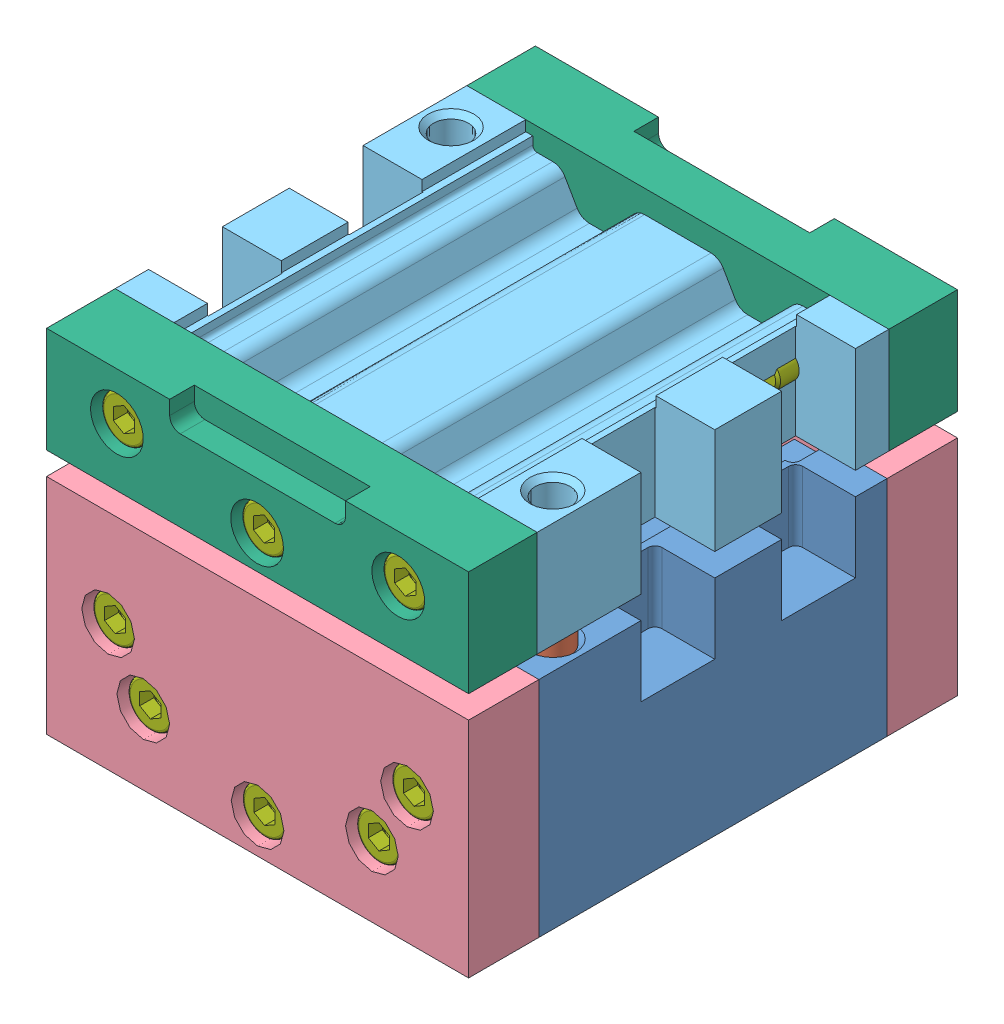
SolidWorks assembly Сборка, configuration По умолчанию. Lengths in mm.
Overall size (120 100 139).
26 component instances, 7 part files, 58 mates.
Components (placement in the parent):
- Матрица пресс-формы трак-1: Матрица пресс-формы трак [По умолчанию] at (94.4955 113.7729 76.599) x (-1 0 0) z (0 -1 0) size (120 99 63.5)
- Направляющая-1: Направляющая [По умолчанию] at (134.3195 83.7729 119.5159) x (0 1 0) z (-0.942376 0 0.334555) size (55 10 10)
- Направляющая-2: Направляющая [По умолчанию] at (30.3195 83.7729 44.5159) x (0 1 0) z (-0.954844 0 0.297108) size (55 10 10)
- Подстановка-1: Подстановка [По умолчанию] at (85.2823 100.5229 55.4864) x (0 1 0) z (-0.987622 0 -0.156852) size (36.5 12 12)
- Подстановка-2: Подстановка [По умолчанию] at (83.6486 100.5229 111.7054) x (0 1 0) z (-0.443057 0 -0.896493) size (36.5 12 12)
- Боковина пресс-формы-1: Боковина пресс-формы [По умолчанию] at (82.3195 82.0229 131.5159) x (1 0 0) z (0 -1 0) size (120 20 63.5)
- Боковина пресс-формы-2: Боковина пресс-формы [По умолчанию] at (82.3195 82.0229 32.5159) x (-1 0 0) z (0 -1 0) size (120 20 63.5)
- Пуансон (на бис, дымись канабис)-2: Пуансон (на бис, дымись канабис) [По умолчанию] at (69.8379 150.2729 72.2482) x (-1 0 0) z (0 0 1) size (120 30 100)
- Боковина пуансона-5: Боковина пуансона [По умолчанию] at (82.3195 135.2729 132.0159) x (1 0 0) z (0 -1 0) size (120 19.5 30)
- Боковина пуансона-6: Боковина пуансона [По умолчанию] at (82.3195 135.2729 32.0159) x (-1 0 0) z (0 -1 0) size (120 19.5 30)
- socket head cap screw 4762_din-2: socket head cap screw 4762_din [EN ISO 4762 M8 x 25 - 25S] at (114.8195 70.2729 149.5159) x (0 0 -1) z (1 0 0) size (33 13 13)
- socket head cap screw 4762_din-3: socket head cap screw 4762_din [EN ISO 4762 M8 x 25 - 25S] at (82.3195 60.2729 149.5159) x (0 0 -1) z (1 0 0) size (33 13 13)
- socket head cap screw 4762_din-4: socket head cap screw 4762_din [EN ISO 4762 M8 x 25 - 25S] at (49.8195 70.2729 149.5159) x (0 0 -1) z (1 0 0) size (33 13 13)
- socket head cap screw 4762_din-6: socket head cap screw 4762_din [EN ISO 4762 M8 x 25 - 25N] at (124.8195 86.2729 149.5159) x (0 0 -1) z (1 0 0) size (33 13 13)
- socket head cap screw 4762_din-7: socket head cap screw 4762_din [EN ISO 4762 M8 x 25 - 25N] at (39.8195 86.2729 149.5159) x (0 0 -1) z (1 0 0) size (33 13 13)
- socket head cap screw 4762_din-8: socket head cap screw 4762_din [EN ISO 4762 M8 x 25 - 25N] at (39.8195 86.2729 14.5159) x (0 0 1) z (-1 0 0) size (33 13 13)
- socket head cap screw 4762_din-9: socket head cap screw 4762_din [EN ISO 4762 M8 x 25 - 25N] at (49.8195 70.2729 14.5159) x (0 0 1) z (-1 0 0) size (33 13 13)
- socket head cap screw 4762_din-10: socket head cap screw 4762_din [EN ISO 4762 M8 x 25 - 25N] at (82.3195 60.2729 14.5159) x (0 0 1) z (-1 0 0) size (33 13 13)
- socket head cap screw 4762_din-11: socket head cap screw 4762_din [EN ISO 4762 M8 x 25 - 25N] at (114.8195 70.2729 14.5159) x (0 0 1) z (-1 0 0) size (33 13 13)
- socket head cap screw 4762_din-12: socket head cap screw 4762_din [EN ISO 4762 M8 x 25 - 25N] at (124.8195 86.2729 14.5159) x (0 0 1) z (-1 0 0) size (33 13 13)
- socket head cap screw 4762_din-13: socket head cap screw 4762_din [EN ISO 4762 M8 x 25 - 25N] at (122.3195 136.7729 149.5159) x (0 0 -1) z (1 0 0) size (33 13 13)
- socket head cap screw 4762_din-14: socket head cap screw 4762_din [EN ISO 4762 M8 x 25 - 25N] at (82.18 129.7729 149.5159) x (0 0 -1) z (1 0 0) size (33 13 13)
- socket head cap screw 4762_din-15: socket head cap screw 4762_din [EN ISO 4762 M8 x 25 - 25N] at (42.3195 136.7729 149.5159) x (0 0 -1) z (1 0 0) size (33 13 13)
- socket head cap screw 4762_din-16: socket head cap screw 4762_din [EN ISO 4762 M8 x 25 - 25N] at (42.3195 136.7729 14.5159) x (0 0 1) z (-1 0 0) size (33 13 13)
- socket head cap screw 4762_din-17: socket head cap screw 4762_din [EN ISO 4762 M8 x 25 - 25N] at (82.4589 129.7729 14.5159) x (0 0 1) z (-1 0 0) size (33 13 13)
- socket head cap screw 4762_din-18: socket head cap screw 4762_din [EN ISO 4762 M8 x 25 - 25N] at (122.3195 136.7729 14.5159) x (0 0 1) z (-1 0 0) size (33 13 13)
Mates (geometry in assembly coordinates):
- Совпадение1: coincident anti-aligned: plane of Матрица пресс-формы трак-1 through (134.3195 83.7729 119.5159) normal (0 1 0); plane of Направляющая-1 through (134.3195 83.7729 119.5159) normal (0 -1 0)
- Концентричный2: concentric anti-aligned: cylinder of Матрица пресс-формы трак-1 through (134.3195 83.7729 119.5159) axis (0 1 0) radius 5; cylinder of Направляющая-1 through (134.3195 83.7729 119.5159) axis (0 -1 0) radius 5
- Совпадение2: coincident anti-aligned: plane of Матрица пресс-формы трак-1 through (30.3195 83.7729 44.5159) normal (0 1 0); plane of Направляющая-2 through (30.3195 83.7729 44.5159) normal (0 -1 0)
- Концентричный3: concentric anti-aligned: cylinder of Матрица пресс-формы трак-1 through (30.3195 83.7729 44.5159) axis (0 1 0) radius 5; cylinder of Направляющая-2 through (30.3195 83.7729 44.5159) axis (0 -1 0) radius 5
- Совпадение3: coincident anti-aligned: plane of Матрица пресс-формы трак-1 through (82.3195 83.7729 55.0159) normal (0 1 0); plane of Подстановка-1 through (82.3195 83.7729 55.0159) normal (0 -1 0)
- Концентричный4: concentric anti-aligned: cylinder of Матрица пресс-формы трак-1 through (82.3195 83.7729 55.0159) axis (0 1 0) radius 6; cylinder of Подстановка-1 through (82.3195 83.7729 55.0159) axis (0 -1 0) radius 6
- Совпадение4: coincident anti-aligned: plane of Матрица пресс-формы трак-1 through (82.3195 83.7729 109.0159) normal (0 1 0); plane of Подстановка-2 through (82.3195 83.7729 109.0159) normal (0 -1 0)
- Концентричный5: concentric anti-aligned: cylinder of Матрица пресс-формы трак-1 through (82.3195 83.7729 109.0159) axis (0 1 0) radius 6; cylinder of Подстановка-2 through (82.3195 83.7729 109.0159) axis (0 -1 0) radius 6
- Совпадение7: coincident anti-aligned: plane of Матрица пресс-формы трак-1 through (142.3195 50.2729 131.5159) normal (0 0 1); plane of Боковина пресс-формы-1 through (82.3195 82.0229 131.5159) normal (0 0 -1)
- Концентричный8: concentric aligned: cylinder of Матрица пресс-формы трак-1 through (82.3195 60.2729 101.5159) axis (0 0 1) radius 3.4; cylinder of Боковина пресс-формы-1 through (82.3195 60.2729 151.5159) axis (0 0 1) radius 4.25
- Концентричный9: concentric aligned: cylinder of Матрица пресс-формы трак-1 through (82.3195 60.2729 62.5159) axis (0 0 -1) radius 3.4; cylinder of Боковина пресс-формы-2 through (82.3195 60.2729 12.5159) axis (0 0 -1) radius 4.25
- Совпадение8: coincident anti-aligned: plane of Матрица пресс-формы трак-1 through (142.3195 50.2729 32.5159) normal (0 0 -1); plane of Боковина пресс-формы-2 through (82.3195 82.0229 32.5159) normal (0 0 1)
- Концентричный11: concentric aligned: cylinder of Направляющая-2 through (30.3195 83.7729 44.5159) axis (0 -1 0) radius 5; cylinder of Пуансон (на бис, дымись канабис)-2 through (30.3195 220.2729 44.5159) axis (0 -1 0) radius 5
- Совпадение9: coincident anti-aligned: circle of Подстановка-1; plane of Пуансон (на бис, дымись канабис)-2 through (69.8379 120.2729 72.2482) normal (0 -1 0)
- Концентричный14: concentric aligned: cylinder of Пуансон (на бис, дымись канабис)-2 through (122.3195 136.7729 105.2659) axis (0 0 1) radius 3.4; cylinder of Боковина пуансона-5 through (122.3195 136.7729 151.5159) axis (0 0 1) radius 4.5
- Совпадение11: coincident anti-aligned: plane of Пуансон (на бис, дымись канабис)-2 through (142.3195 120.2729 132.0159) normal (0 0 1); plane of Боковина пуансона-5 through (82.3195 135.2729 132.0159) normal (0 0 -1)
- Концентричный15: concentric aligned: cylinder of Пуансон (на бис, дымись канабис)-2 through (122.3195 136.7729 58.7659) axis (0 0 -1) radius 3.4; cylinder of Боковина пуансона-6 through (122.3195 136.7729 12.5159) axis (0 0 -1) radius 4.5
- Совпадение12: coincident anti-aligned: plane of Пуансон (на бис, дымись канабис)-2 through (142.3195 120.2729 32.0159) normal (0 0 -1); plane of Боковина пуансона-6 through (82.3195 135.2729 32.0159) normal (0 0 1)
- Параллельность1: parallel aligned: cylinder of Направляющая-1 through (134.3195 83.7729 119.5159) axis (0 -1 0) radius 5; cylinder of Пуансон (на бис, дымись канабис)-2 through (134.2575 220.2729 119.5159) axis (0 -1 0) radius 5
- Концентричный17: concentric aligned: cylinder of Направляющая-2 through (30.3195 83.7729 44.5159) axis (0 -1 0) radius 5; cylinder of Пуансон (на бис, дымись канабис)-2 through (30.3195 220.2729 44.5159) axis (0 -1 0) radius 5
- Совпадение13: coincident aligned: plane of Пуансон (на бис, дымись канабис)-2 through (22.3195 120.2729 32.0159) normal (-1 0 0); plane of Боковина пуансона-5 through (22.3195 120.2729 151.5159) normal (-1 0 0)
- Совпадение14: coincident aligned: plane of Пуансон (на бис, дымись канабис)-2 through (22.3195 120.2729 32.0159) normal (-1 0 0); plane of Боковина пуансона-6 through (22.3195 120.2729 12.5159) normal (-1 0 0)
- Параллельность2: parallel aligned: cylinder of Боковина пресс-формы-1 through (124.8195 86.2729 151.5159) axis (0 0 1) radius 4.25; cylinder of Матрица пресс-формы трак-1 through (124.8195 86.2729 101.5159) axis (0 0 1) radius 3.4
- Совпадение16: coincident aligned: plane of Матрица пресс-формы трак-1 through (142.3195 50.2729 32.5159) normal (1 0 0); plane of Боковина пресс-формы-1 through (142.3195 50.2729 151.5159) normal (1 0 0)
- Совпадение17: coincident aligned: plane of Матрица пресс-формы трак-1 through (142.3195 50.2729 32.5159) normal (1 0 0); plane of Боковина пресс-формы-2 through (142.3195 50.2729 12.5159) normal (1 0 0)
- Совпадение18: coincident aligned: plane of Матрица пресс-формы трак-1 through (142.3195 50.2729 32.5159) normal (1 0 0); plane of Пуансон (на бис, дымись канабис)-2 through (142.3195 120.2729 32.0159) normal (1 0 0)
- Концентричный19: concentric aligned: cylinder of Боковина пресс-формы-1 through (114.8195 70.2729 151.5159) axis (0 0 1) radius 4.25; cylinder of socket head cap screw 4762_din-2 through (114.8195 70.2729 181.2659) axis (0 0 1) radius 6.5
- Совпадение20: coincident anti-aligned: plane of Боковина пресс-формы-1 through (119.0695 70.2729 141.5159) normal (0 0 1); plane of socket head cap screw 4762_din-2 through (114.8195 76.7729 141.5159) normal (0 0 -1)
- Концентричный20: concentric aligned: cylinder of Боковина пресс-формы-1 through (82.3195 60.2729 151.5159) axis (0 0 1) radius 7.5; cylinder of socket head cap screw 4762_din-3 through (82.3195 60.2729 181.2659) axis (0 0 1) radius 6.5
- Совпадение21: coincident anti-aligned: plane of Боковина пресс-формы-1 through (86.5695 60.2729 141.5159) normal (0 0 1); plane of socket head cap screw 4762_din-3 through (82.3195 66.7729 141.5159) normal (0 0 -1)
- Концентричный21: concentric aligned: cylinder of Боковина пресс-формы-1 through (49.8195 70.2729 151.5159) axis (0 0 1) radius 7.5; cylinder of socket head cap screw 4762_din-4 through (49.8195 70.2729 181.2659) axis (0 0 1) radius 6.5
- Совпадение22: coincident anti-aligned: plane of Боковина пресс-формы-1 through (54.0695 70.2729 141.5159) normal (0 0 1); plane of socket head cap screw 4762_din-4 through (49.8195 76.7729 141.5159) normal (0 0 -1)
- Концентричный23: concentric aligned: cylinder of Боковина пресс-формы-1 through (124.8195 86.2729 151.5159) axis (0 0 1) radius 4.25; cylinder of socket head cap screw 4762_din-6 through (124.8195 86.2729 181.2659) axis (0 0 1) radius 6.5
- Совпадение23: coincident anti-aligned: plane of Боковина пресс-формы-1 through (129.0695 86.2729 141.5159) normal (0 0 1); plane of socket head cap screw 4762_din-6 through (124.8195 92.7729 141.5159) normal (0 0 -1)
- Концентричный24: concentric aligned: cylinder of Боковина пресс-формы-1 through (39.8195 86.2729 151.5159) axis (0 0 1) radius 4.25; cylinder of socket head cap screw 4762_din-7 through (39.8195 86.2729 181.2659) axis (0 0 1) radius 6.5
- Совпадение24: coincident anti-aligned: plane of Боковина пресс-формы-1 through (44.0695 86.2729 141.5159) normal (0 0 1); plane of socket head cap screw 4762_din-7 through (39.8195 92.7729 141.5159) normal (0 0 -1)
- Концентричный25: concentric aligned: cylinder of Боковина пресс-формы-2 through (39.8195 86.2729 12.5159) axis (0 0 -1) radius 7.5; cylinder of socket head cap screw 4762_din-8 through (39.8195 86.2729 -17.2341) axis (0 0 -1) radius 6.5
- Совпадение25: coincident anti-aligned: plane of Боковина пресс-формы-2 through (35.5695 86.2729 22.5159) normal (0 0 -1); plane of socket head cap screw 4762_din-8 through (39.8195 92.7729 22.5159) normal (0 0 1)
- Концентричный26: concentric aligned: cylinder of Боковина пресс-формы-2 through (49.8195 70.2729 12.5159) axis (0 0 -1) radius 4.25; cylinder of socket head cap screw 4762_din-9 through (49.8195 70.2729 -17.2341) axis (0 0 -1) radius 6.5
- Совпадение26: coincident anti-aligned: plane of Боковина пресс-формы-2 through (45.5695 70.2729 22.5159) normal (0 0 -1); plane of socket head cap screw 4762_din-9 through (49.8195 76.7729 22.5159) normal (0 0 1)
- Концентричный27: concentric aligned: cylinder of Боковина пресс-формы-2 through (82.3195 60.2729 12.5159) axis (0 0 -1) radius 7.5; cylinder of socket head cap screw 4762_din-10 through (82.3195 60.2729 -17.2341) axis (0 0 -1) radius 6.5
- Совпадение27: coincident anti-aligned: plane of Боковина пресс-формы-2 through (78.0695 60.2729 22.5159) normal (0 0 -1); plane of socket head cap screw 4762_din-10 through (82.3195 66.7729 22.5159) normal (0 0 1)
- Концентричный28: concentric aligned: cylinder of Боковина пресс-формы-2 through (114.8195 70.2729 12.5159) axis (0 0 -1) radius 4.25; cylinder of socket head cap screw 4762_din-11 through (114.8195 70.2729 -17.2341) axis (0 0 -1) radius 6.5
- Совпадение28: coincident anti-aligned: plane of Боковина пресс-формы-2 through (110.5695 70.2729 22.5159) normal (0 0 -1); plane of socket head cap screw 4762_din-11 through (114.8195 76.7729 22.5159) normal (0 0 1)
- Концентричный29: concentric aligned: cylinder of Боковина пресс-формы-2 through (124.8195 86.2729 12.5159) axis (0 0 -1) radius 7.5; cylinder of socket head cap screw 4762_din-12 through (124.8195 86.2729 -17.2341) axis (0 0 -1) radius 6.5
- Совпадение29: coincident anti-aligned: plane of Боковина пресс-формы-2 through (120.5695 86.2729 22.5159) normal (0 0 -1); plane of socket head cap screw 4762_din-12 through (124.8195 92.7729 22.5159) normal (0 0 1)
- Концентричный30: concentric aligned: cylinder of Боковина пуансона-5 through (122.3195 136.7729 151.5159) axis (0 0 1) radius 4.5; cylinder of socket head cap screw 4762_din-13 through (122.3195 136.7729 181.2659) axis (0 0 1) radius 6.5
- Совпадение30: coincident anti-aligned: plane of Боковина пуансона-5 through (126.8195 136.7729 141.5159) normal (0 0 1); plane of socket head cap screw 4762_din-13 through (122.3195 143.2729 141.5159) normal (0 0 -1)
- Концентричный31: concentric aligned: cylinder of Боковина пуансона-5 through (82.18 129.7729 151.5159) axis (0 0 1) radius 4.5; cylinder of socket head cap screw 4762_din-14 through (82.18 129.7729 181.2659) axis (0 0 1) radius 6.5
- Совпадение31: coincident anti-aligned: plane of Боковина пуансона-5 through (86.68 129.7729 141.5159) normal (0 0 1); plane of socket head cap screw 4762_din-14 through (82.18 136.2729 141.5159) normal (0 0 -1)
- Концентричный32: concentric aligned: cylinder of Боковина пуансона-5 through (42.3195 136.7729 151.5159) axis (0 0 1) radius 7.5; cylinder of socket head cap screw 4762_din-15 through (42.3195 136.7729 181.2659) axis (0 0 1) radius 6.5
- Совпадение32: coincident anti-aligned: plane of Боковина пуансона-5 through (46.8195 136.7729 141.5159) normal (0 0 1); plane of socket head cap screw 4762_din-15 through (42.3195 143.2729 141.5159) normal (0 0 -1)
- Концентричный33: concentric aligned: cylinder of Боковина пуансона-6 through (42.3195 136.7729 12.5159) axis (0 0 -1) radius 4.5; cylinder of socket head cap screw 4762_din-16 through (42.3195 136.7729 -17.2341) axis (0 0 -1) radius 6.5
- Совпадение33: coincident anti-aligned: plane of Боковина пуансона-6 through (37.8195 136.7729 22.5159) normal (0 0 -1); plane of socket head cap screw 4762_din-16 through (42.3195 143.2729 22.5159) normal (0 0 1)
- Концентричный34: concentric aligned: cylinder of Боковина пуансона-6 through (82.4589 129.7729 12.5159) axis (0 0 -1) radius 4.5; cylinder of socket head cap screw 4762_din-17 through (82.4589 129.7729 -17.2341) axis (0 0 -1) radius 6.5
- Совпадение34: coincident anti-aligned: plane of Боковина пуансона-6 through (77.9589 129.7729 22.5159) normal (0 0 -1); plane of socket head cap screw 4762_din-17 through (82.4589 136.2729 22.5159) normal (0 0 1)
- Концентричный35: concentric aligned: cylinder of Боковина пуансона-6 through (122.3195 136.7729 12.5159) axis (0 0 -1) radius 4.5; cylinder of socket head cap screw 4762_din-18 through (122.3195 136.7729 -17.2341) axis (0 0 -1) radius 6.5
- Совпадение35: coincident anti-aligned: plane of Боковина пуансона-6 through (117.8195 136.7729 22.5159) normal (0 0 -1); plane of socket head cap screw 4762_din-18 through (122.3195 143.2729 22.5159) normal (0 0 1)
